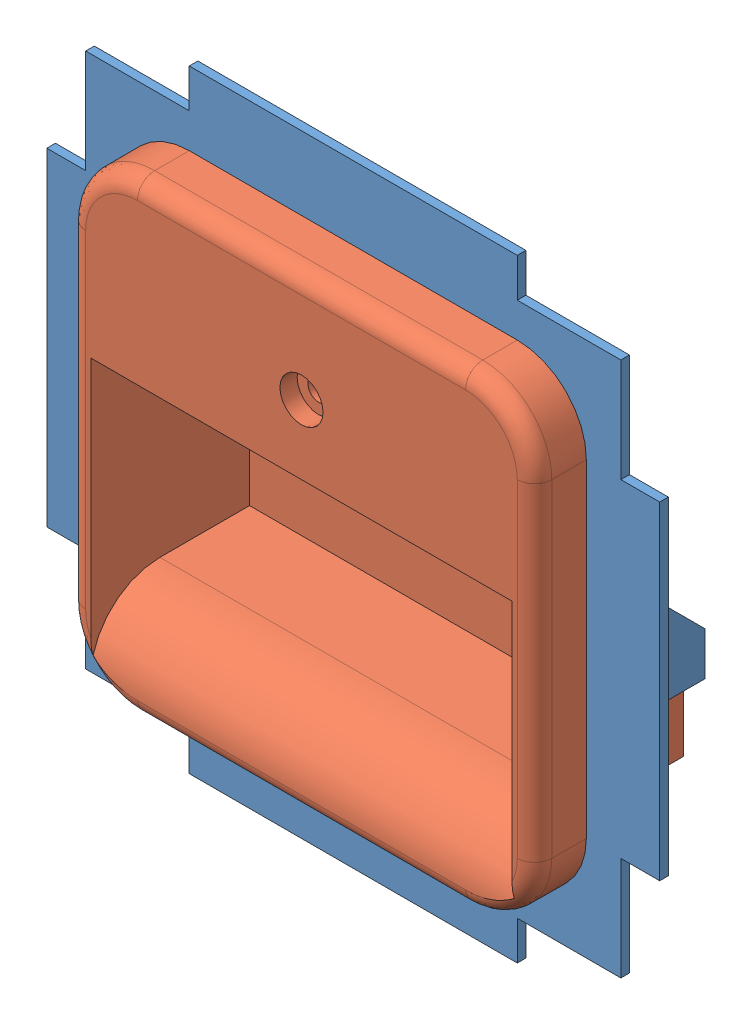
SolidWorks assembly Keystone-Unterputzeinsatz, configuration 3er. Lengths in mm.
Overall size (71 71 21.25).
2 component instances, 2 part files, 6 mates.
Components (placement in the parent):
- Keystone-Montageplatte-1: Keystone-Montageplatte [3er] at (-35.5 -35.5 -6) x (-1 0 0) z (0 0 -1) size (71 71 14.87)
- Keystone-Frontplatte-1: Keystone-Frontplatte [3er] at (-35.5 -35.5 0) size (54 54 19.77)
Mates (geometry in assembly coordinates):
- Deckungsgleich1: coincident anti-aligned: plane of Keystone-Montageplatte-1 through (-35.5 20.7503 -6) normal (0 0 1); plane of Keystone-Frontplatte-1 through (-54.5 1.7503 -6) normal (0 0 -1)
- Konzentrisch1: concentric aligned: cylinder of Keystone-Montageplatte-1 through (-35.5 35.2503 -7) axis (0 0 1) radius 1.25; cylinder of Keystone-Frontplatte-1 through (-35.5 35.2503 -10) axis (0 0 1) radius 1.25
- Parallel1: parallel aligned: plane of Keystone-Montageplatte-1 through (-16.5 -14.7497 -7) normal (0 -1 0); plane of Keystone-Frontplatte-1 through (-54.5 -6.2497 -6) normal (0 -1 0)
- Deckungsgleich2: coincident aligned: plane of Keystone-Frontplatte-1 through (-54.5 -54.5 0) normal (0 0 1); plane of assembly
- Deckungsgleich3: coincident aligned: plane of Keystone-Montageplatte-1 through (0 -16.5 -7) normal (1 0 0); plane of assembly
- Deckungsgleich4: coincident aligned: plane of Keystone-Montageplatte-1 through (-54.5 0 -7) normal (0 1 0); plane of assembly
